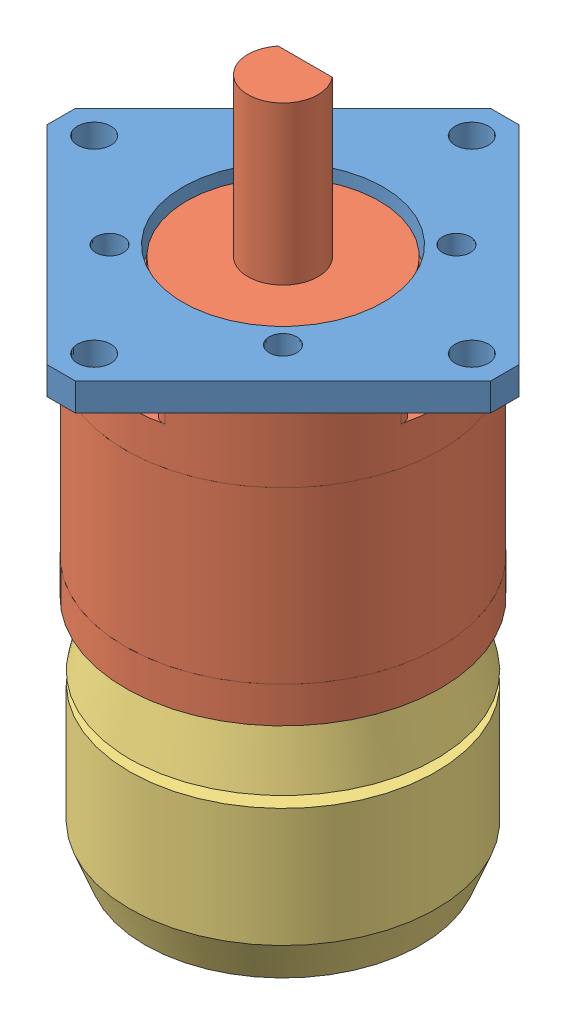
SolidWorks assembly 3536 gearmotor with facemount, configuration Default. Lengths in mm.
Overall size (53.88 81.68 53.88).
5 component instances, 3 part files, 0 mates.
Components (placement in the parent):
- 3536 gearmotor with facemount.step-1: 3536 gearmotor with facemount.step [Default] at origin size (53.88 81.68 53.88)
  - 36toBBadapter.step-1: 36toBBadapter.step [Default] at origin size (53.88 3.17 53.88)
    - Default.step-1: Default.step [Default] at (16.2622 10.4796 0) x (0.707107 0 0.707107) z (0 -1 0) size (38.1 38.1 3.17)
  - 36mm gear box.step-1: 36mm gear box.step [Default] at (16.2622 -20.2544 0) size (36 51.67 36)
  - 3530.step-1: 3530.step [Default] at (16.2622 -17.3786 0) x (0 -1 0) z (0 0 1) size (31 35 35)
